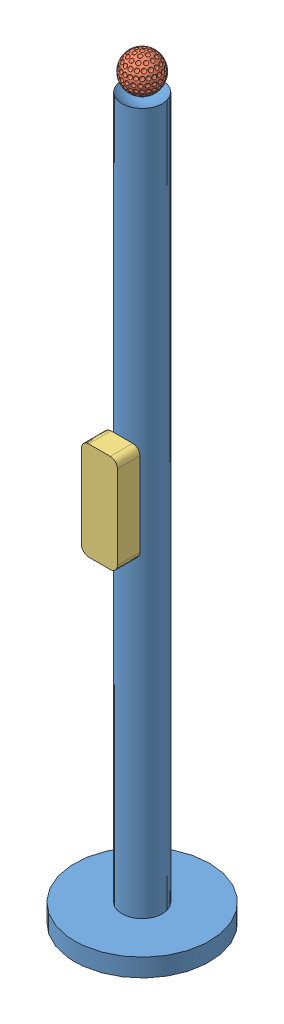
SolidWorks assembly Assem3, configuration pinger. Lengths in mm.
Overall size (150 839.75 150).
3 component instances, 3 part files, 7 mates.
Components (placement in the parent):
- flare_4-1: flare_4 [Pinger] at origin size (150 800 150)
- golf_ball-1: golf_ball [Default] at (0 799.873 0) size (40 39.75 40)
- pinger-1: pinger [Default] at (0 424.5 22.5) size (40 109 25)
Mates (geometry in assembly coordinates):
- Coincident1: coincident: point of flare_4-1; point of golf_ball-1
- Parallel1: parallel aligned: plane of golf_ball-1 through (0 799.873 0) normal (0 1 0)
- Coincident3: coincident aligned: plane of golf_ball-1 through (0 799.873 0) normal (0 0 1)
- Coincident4: coincident aligned: plane of golf_ball-1 through (0 799.873 0) normal (1 0 0)
- Coincident5: coincident aligned: line of flare_4-1 through (-20 479 22.5) axis (0 -1 0); line of pinger-1 through (-20 471 22.5) axis (0 -1 0)
- Coincident6: coincident anti-aligned: line of flare_4-1 through (-20 479 22.5) axis (1 0 0); line of pinger-1 through (12 479 22.5) axis (-1 0 0)
- Coincident7: coincident anti-aligned: line of flare_4-1 through (20 479 22.5) axis (0 -1 0); line of pinger-1 through (20 378 22.5) axis (0 1 0)
